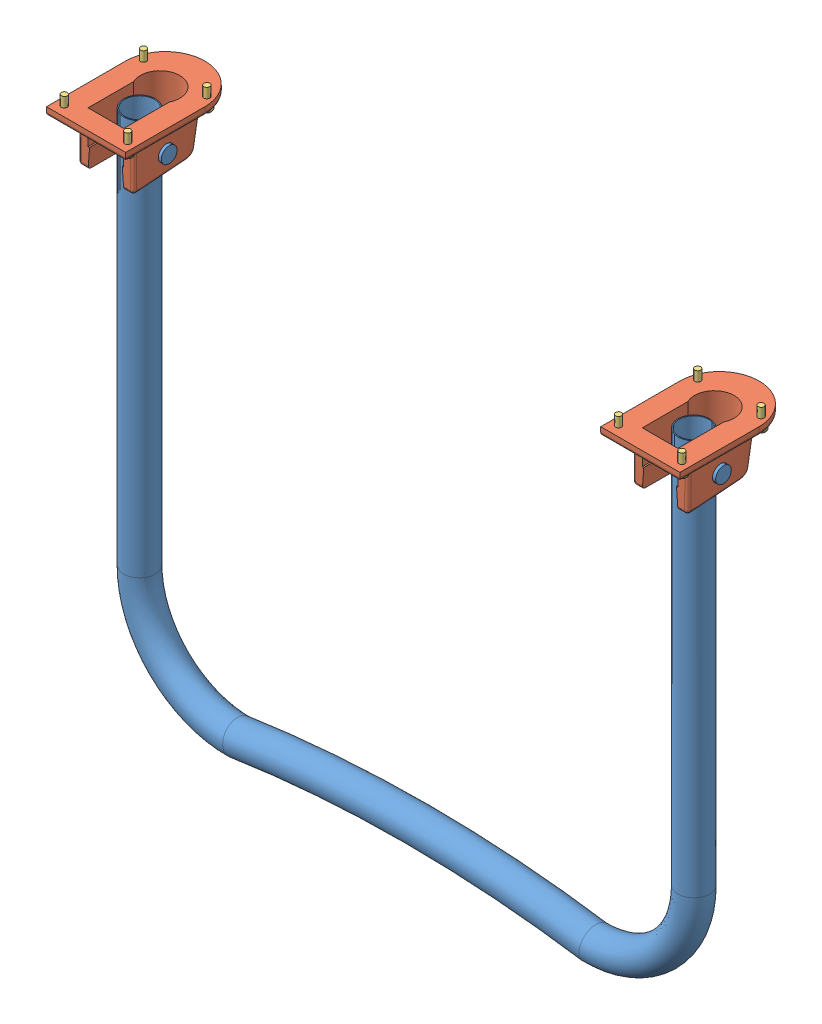
SolidWorks assembly LegAsm, configuration Default. Lengths in mm.
Overall size (319.97 267.4 60).
11 component instances, 3 part files, 42 mates.
Components (placement in the parent):
- leg-1: leg [Default] at origin size (309.97 258.4 16.94)
- connectionNotch-1: connectionNotch [Default] at (139.985 4 27) x (-1 0 0) z (0 0 1) size (40 27 60)
- connectionNotch-2: connectionNotch [Default] at (-139.985 4 27) x (-1 0 0) z (0 0 1) size (40 27 60)
- fastener-1: fastener [Default] at (-123.985 -2 -18) x (-1 0 0) z (0 0 -1) size (5 11 5)
- fastener-2: fastener [Default] at (-123.985 -2 22) size (5 11 5)
- fastener-3: fastener [Default] at (-155.985 -2 22) size (5 11 5)
- fastener-4: fastener [Default] at (-155.985 -2 -18) size (5 11 5)
- fastener-5: fastener [Default] at (155.985 -2 22) size (5 11 5)
- fastener-6: fastener [Default] at (123.985 -2 22) size (5 11 5)
- fastener-7: fastener [Default] at (155.985 -2 -18) size (5 11 5)
- fastener-8: fastener [Default] at (123.985 -2 -18) size (5 11 5)
Mates (geometry in assembly coordinates):
- Coincident1: coincident aligned: plane of leg-1 through (0 0 0) normal (0 0 1)
- Coincident2: coincident aligned: plane of leg-1 through (0 0 0) normal (0 1 0)
- Coincident3: coincident aligned: plane of leg-1 through (0 0 0) normal (1 0 0)
- Coincident4: coordinate: point of leg-1
- LimitAngle1: limit planar angle = 3.141593 rad aligned: plane of connectionNotch-1 through (139.985 4 27) normal (0 -1 0); plane of leg-1 through (0 0 0) normal (0 1 0)
- Concentric1: concentric aligned: cylinder of leg-1 through (151.985 -13 0) axis (-1 0 0) radius 2.475; cylinder of connectionNotch-1 through (159.985 -13 0) axis (-1 0 0) radius 2.5
- Coincident6: coincident anti-aligned: plane of leg-1 through (151.985 -13 0) normal (-1 0 0); plane of connectionNotch-1 through (151.985 -13 0) normal (1 0 0)
- LimitAngle2: limit planar angle = 3.141593 rad aligned: plane of connectionNotch-2 through (-139.985 4 27) normal (0 -1 0); plane of leg-1 through (0 0 0) normal (0 1 0)
- Concentric2: concentric anti-aligned: cylinder of leg-1 through (-151.985 -13 0) axis (1 0 0) radius 2.475; cylinder of connectionNotch-2 through (-119.985 -13 0) axis (-1 0 0) radius 2.5
- Coincident8: coincident anti-aligned: plane of leg-1 through (-151.985 -13 0) normal (1 0 0); plane of connectionNotch-2 through (-151.985 -13 0) normal (-1 0 0)
- Concentric3: concentric aligned: cylinder of connectionNotch-2 through (-123.985 0 -18) axis (0 -1 0) radius 1.5; cylinder of fastener-1 through (-123.985 9 -18) axis (0 -1 0) radius 1.49
- Coincident9: coincident anti-aligned: plane of connectionNotch-2 through (-139.985 0 -13) normal (0 -1 0); plane of fastener-1 through (-123.985 0 -18) normal (0 1 0)
- Parallel2: parallel aligned: plane of connectionNotch-2 through (-139.985 4 27) normal (-1 0 0); plane of fastener-1 through (-123.985 -2 -18) normal (-1 0 0)
- Parallel3: parallel anti-aligned: plane of connectionNotch-2 through (-139.985 4 27) normal (0 0 1); plane of fastener-1 through (-123.985 -2 -18) normal (0 0 -1)
- Coincident12: coincident anti-aligned: plane of connectionNotch-2 through (-139.985 0 -13) normal (0 -1 0); plane of fastener-2 through (-123.985 0 22) normal (0 1 0)
- Concentric4: concentric aligned: cylinder of connectionNotch-2 through (-123.985 0 22) axis (0 -1 0) radius 1.5; cylinder of fastener-2 through (-123.985 9 22) axis (0 -1 0) radius 1.49
- Parallel4: parallel aligned: plane of connectionNotch-2 through (-139.985 4 27) normal (0 0 1); plane of fastener-2 through (-123.985 -2 22) normal (0 0 1)
- Parallel5: parallel anti-aligned: plane of connectionNotch-2 through (-139.985 4 27) normal (-1 0 0); plane of fastener-2 through (-123.985 -2 22) normal (1 0 0)
- Coincident14: coincident anti-aligned: plane of connectionNotch-2 through (-139.985 0 -13) normal (0 -1 0); plane of fastener-3 through (-155.985 0 22) normal (0 1 0)
- Concentric5: concentric aligned: cylinder of connectionNotch-2 through (-155.985 0 22) axis (0 -1 0) radius 1.5; cylinder of fastener-3 through (-155.985 9 22) axis (0 -1 0) radius 1.49
- Parallel6: parallel anti-aligned: plane of connectionNotch-2 through (-139.985 4 27) normal (-1 0 0); plane of fastener-3 through (-155.985 -2 22) normal (1 0 0)
- Parallel7: parallel aligned: plane of connectionNotch-2 through (-139.985 4 27) normal (0 0 1); plane of fastener-3 through (-155.985 -2 22) normal (0 0 1)
- Coincident16: coincident anti-aligned: plane of connectionNotch-2 through (-139.985 0 -13) normal (0 -1 0); plane of fastener-4 through (-155.985 0 -18) normal (0 1 0)
- Concentric6: concentric aligned: cylinder of connectionNotch-2 through (-155.985 0 -18) axis (0 -1 0) radius 1.5; cylinder of fastener-4 through (-155.985 9 -18) axis (0 -1 0) radius 1.49
- Parallel8: parallel aligned: plane of connectionNotch-2 through (-139.985 4 27) normal (0 0 1); plane of fastener-4 through (-155.985 -2 -18) normal (0 0 1)
- Parallel9: parallel anti-aligned: plane of connectionNotch-2 through (-139.985 4 27) normal (-1 0 0); plane of fastener-4 through (-155.985 -2 -18) normal (1 0 0)
- Coincident18: coincident anti-aligned: plane of connectionNotch-1 through (139.985 0 -13) normal (0 -1 0); plane of fastener-5 through (155.985 0 22) normal (0 1 0)
- Concentric7: concentric aligned: cylinder of connectionNotch-1 through (155.985 0 22) axis (0 -1 0) radius 1.5; cylinder of fastener-5 through (155.985 9 22) axis (0 -1 0) radius 1.49
- Parallel10: parallel aligned: plane of connectionNotch-1 through (139.985 4 27) normal (0 0 1); plane of fastener-5 through (155.985 -2 22) normal (0 0 1)
- Parallel11: parallel anti-aligned: plane of connectionNotch-1 through (139.985 4 27) normal (-1 0 0); plane of fastener-5 through (155.985 -2 22) normal (1 0 0)
- Coincident20: coincident anti-aligned: plane of connectionNotch-1 through (139.985 0 -13) normal (0 -1 0); plane of fastener-6 through (123.985 0 22) normal (0 1 0)
- Concentric8: concentric aligned: cylinder of connectionNotch-1 through (123.985 0 22) axis (0 -1 0) radius 1.5; cylinder of fastener-6 through (123.985 9 22) axis (0 -1 0) radius 1.49
- Parallel12: parallel aligned: plane of connectionNotch-1 through (139.985 4 27) normal (0 0 1); plane of fastener-6 through (123.985 -2 22) normal (0 0 1)
- Parallel13: parallel anti-aligned: plane of connectionNotch-1 through (139.985 4 27) normal (-1 0 0); plane of fastener-6 through (123.985 -2 22) normal (1 0 0)
- Coincident22: coincident anti-aligned: plane of connectionNotch-1 through (139.985 0 -13) normal (0 -1 0); plane of fastener-7 through (155.985 0 -18) normal (0 1 0)
- Concentric9: concentric aligned: cylinder of connectionNotch-1 through (155.985 0 -18) axis (0 -1 0) radius 1.5; cylinder of fastener-7 through (155.985 9 -18) axis (0 -1 0) radius 1.49
- Parallel14: parallel aligned: plane of connectionNotch-1 through (139.985 4 27) normal (0 0 1); plane of fastener-7 through (155.985 -2 -18) normal (0 0 1)
- Parallel15: parallel anti-aligned: plane of connectionNotch-1 through (139.985 4 27) normal (-1 0 0); plane of fastener-7 through (155.985 -2 -18) normal (1 0 0)
- Coincident24: coincident anti-aligned: plane of connectionNotch-1 through (139.985 0 -13) normal (0 -1 0); plane of fastener-8 through (123.985 0 -18) normal (0 1 0)
- Concentric10: concentric aligned: cylinder of connectionNotch-1 through (123.985 0 -18) axis (0 -1 0) radius 1.5; cylinder of fastener-8 through (123.985 9 -18) axis (0 -1 0) radius 1.49
- Parallel16: parallel aligned: plane of connectionNotch-1 through (139.985 4 27) normal (0 0 1); plane of fastener-8 through (123.985 -2 -18) normal (0 0 1)
- Parallel17: parallel anti-aligned: plane of connectionNotch-1 through (139.985 4 27) normal (-1 0 0); plane of fastener-8 through (123.985 -2 -18) normal (1 0 0)
